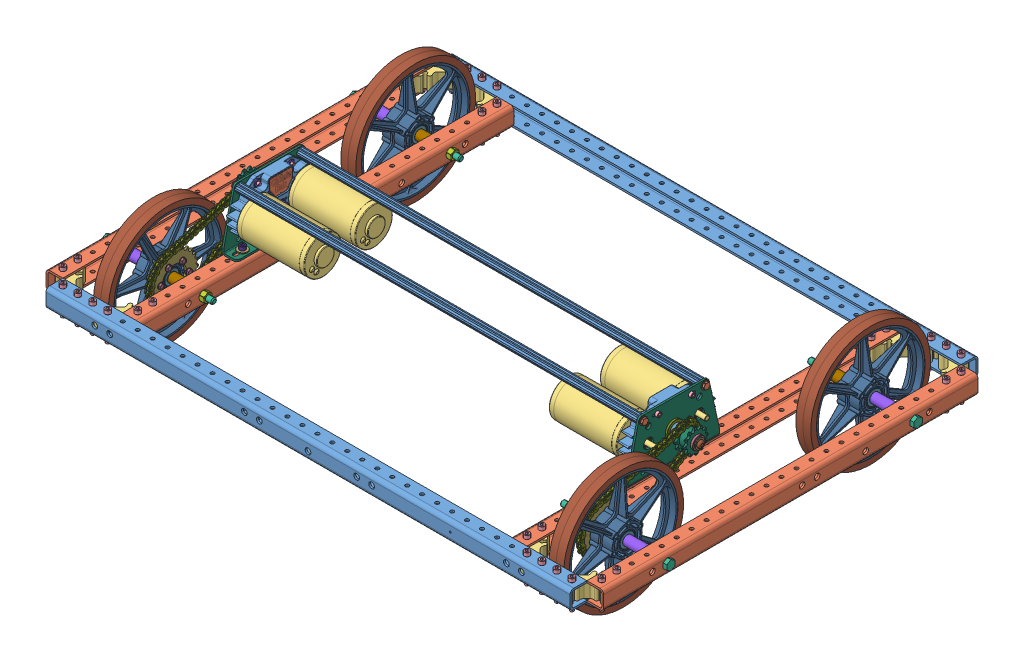
SolidWorks assembly 2011C-BaseWheelsCIMpleBoxWIDE, configuration Default. Lengths in mm.
Overall size (966.2 283.99 712.2).
231 component instances, 38 part files, 61 mates.
Components (placement in the parent):
- C-Base-Triangle-Mounts-no-bracket-WIDE-1: C-Base-Triangle-Mounts-no-bracket-WIDE [Default] at origin size (966.2 50.8 712.2)
  - C channel Outer-1: C channel Outer [Default] at (0 0 -317.4979) x (0 -1 0) z (0 0 1) size (31.75 889 28.57)
  - Short C channel-1: Short C channel [for WIDE frame] at (444.5 0 -25.4) x (0 1 0) z (-1 0 0) size (31.75 635 28.57)
  - Corner_Extrusion-2: Corner_Extrusion [Default] at (437.7662 0 -310.765) x (-0.707157 0 -0.707057) z (0 -1 0) size (90.51 36.63 25.4)
  - SHCS_1-6: SHCS_1 [1.75] at (457.2 -3.175 -279.4) x (0 -1 0) z (0 0 -1) size (50.8 9.4 9.4)
  - SHCS_1-7: SHCS_1 [1.75] at (457.2 -3.175 -304.8) x (0 -1 0) z (0 0 -1) size (50.8 9.4 9.4)
  - SHCS_1-8: SHCS_1 [1.75] at (431.8 -3.175 -330.1979) x (0 -1 0) z (0 0 -1) size (50.8 9.4 9.4)
  - SHCS_1-9: SHCS_1 [1.75] at (406.4 -3.175 -330.1979) x (0 -1 0) z (0 0 -1) size (50.8 9.4 9.4)
  - Quarer20_Nut-5: Quarer20_Nut [Default] at (457.2 -18.8595 -279.4) x (0.837169 0 -0.546944) z (0.546944 0 0.837169) size (14.11 5.97 11.11)
  - Quarer20_Nut-6: Quarer20_Nut [Default] at (457.2 -18.8595 -304.8) x (0.837169 0 -0.546944) z (0.546944 0 0.837169) size (14.11 5.97 11.11)
  - Quarer20_Nut-9: Quarer20_Nut [Default] at (406.4 -18.8595 -330.1979) x (0.837169 0 -0.546944) z (0.546944 0 0.837169) size (14.11 5.97 11.11)
  - Quarer20_Nut-12: Quarer20_Nut [Default] at (431.8 -18.8595 -330.1979) x (0.837169 0 -0.546944) z (0.546944 0 0.837169) size (14.11 5.97 11.11)
  - C channel Outer-4: C channel Outer [Default] at (0 0 317.4979) x (0 -1 0) z (0 0 -1) size (31.75 889 28.57)
  - Short C channel-3: Short C channel [for WIDE frame] at (-444.5 0 25.4) x (0 1 0) z (1 0 0) size (31.75 635 28.57)
  - SHCS_1-18: SHCS_1 [1.75] at (330.2 -3.175 -279.4) x (0 -1 0) z (0 0 1) size (50.8 9.4 9.4)
  - SHCS_1-19: SHCS_1 [1.75] at (330.2 -3.175 -304.8) x (0 -1 0) z (0 0 1) size (50.8 9.4 9.4)
  - SHCS_1-20: SHCS_1 [1.75] at (355.6 -3.175 -330.1979) x (0 -1 0) z (0 0 1) size (50.8 9.4 9.4)
  - SHCS_1-21: SHCS_1 [1.75] at (381 -3.175 -330.1979) x (0 -1 0) z (0 0 1) size (50.8 9.4 9.4)
  - Quarer20_Nut-21: Quarer20_Nut [Default] at (330.2 -18.8595 -279.4) x (-0.837169 0 -0.546944) z (0.546944 0 -0.837169) size (14.11 5.97 11.11)
  - Quarer20_Nut-22: Quarer20_Nut [Default] at (330.2 -18.8595 -304.8) x (-0.837169 0 -0.546944) z (0.546944 0 -0.837169) size (14.11 5.97 11.11)
  - Quarer20_Nut-23: Quarer20_Nut [Default] at (381 -18.8595 -330.1979) x (-0.837169 0 -0.546944) z (0.546944 0 -0.837169) size (14.11 5.97 11.11)
  - Quarer20_Nut-24: Quarer20_Nut [Default] at (355.6 -18.8595 -330.1979) x (-0.837169 0 -0.546944) z (0.546944 0 -0.837169) size (14.11 5.97 11.11)
  - Corner_Extrusion-5: Corner_Extrusion [Default] at (349.6338 0 -310.765) x (0.707157 0 -0.707057) z (0 1 0) size (90.51 36.63 25.4)
  - SHCS_1-30: SHCS_1 [1.75] at (330.2 -3.175 279.4) x (0 -1 0) z (0 0 1) size (50.8 9.4 9.4)
  - SHCS_1-31: SHCS_1 [1.75] at (330.2 -3.175 304.8) x (0 -1 0) z (0 0 1) size (50.8 9.4 9.4)
  - SHCS_1-32: SHCS_1 [1.75] at (355.6 -3.175 330.1979) x (0 -1 0) z (0 0 1) size (50.8 9.4 9.4)
  - SHCS_1-33: SHCS_1 [1.75] at (381 -3.175 330.1979) x (0 -1 0) z (0 0 1) size (50.8 9.4 9.4)
  - Quarer20_Nut-33: Quarer20_Nut [Default] at (330.2 -18.8595 279.4) x (-0.837169 0 0.546944) z (-0.546944 0 -0.837169) size (14.11 5.97 11.11)
  - Quarer20_Nut-34: Quarer20_Nut [Default] at (330.2 -18.8595 304.8) x (-0.837169 0 0.546944) z (-0.546944 0 -0.837169) size (14.11 5.97 11.11)
  - Quarer20_Nut-35: Quarer20_Nut [Default] at (381 -18.8595 330.1979) x (-0.837169 0 0.546944) z (-0.546944 0 -0.837169) size (14.11 5.97 11.11)
  - Quarer20_Nut-36: Quarer20_Nut [Default] at (355.6 -18.8595 330.1979) x (-0.837169 0 0.546944) z (-0.546944 0 -0.837169) size (14.11 5.97 11.11)
  - Corner_Extrusion-8: Corner_Extrusion [Default] at (349.6338 0 310.765) x (0.707157 0 0.707057) z (0 -1 0) size (90.51 36.63 25.4)
  - SHCS_1-34: SHCS_1 [1.75] at (457.2 -3.175 279.4) x (0 -1 0) z (0 0 -1) size (50.8 9.4 9.4)
  - SHCS_1-35: SHCS_1 [1.75] at (457.2 -3.175 304.8) x (0 -1 0) z (0 0 -1) size (50.8 9.4 9.4)
  - SHCS_1-36: SHCS_1 [1.75] at (431.8 -3.175 330.1979) x (0 -1 0) z (0 0 -1) size (50.8 9.4 9.4)
  - SHCS_1-37: SHCS_1 [1.75] at (406.4 -3.175 330.1979) x (0 -1 0) z (0 0 -1) size (50.8 9.4 9.4)
  - Corner_Extrusion-9: Corner_Extrusion [Default] at (437.7662 0 310.765) x (-0.707157 0 0.707057) z (0 1 0) size (90.51 36.63 25.4)
  - Quarer20_Nut-37: Quarer20_Nut [Default] at (457.2 -18.8595 279.4) x (0.837169 0 0.546944) z (-0.546944 0 0.837169) size (14.11 5.97 11.11)
  - Quarer20_Nut-38: Quarer20_Nut [Default] at (457.2 -18.8595 304.8) x (0.837169 0 0.546944) z (-0.546944 0 0.837169) size (14.11 5.97 11.11)
  - Quarer20_Nut-39: Quarer20_Nut [Default] at (431.8 -18.8595 330.1979) x (0.837169 0 0.546944) z (-0.546944 0 0.837169) size (14.11 5.97 11.11)
  - Quarer20_Nut-40: Quarer20_Nut [Default] at (406.4 -18.8595 330.1979) x (0.837169 0 0.546944) z (-0.546944 0 0.837169) size (14.11 5.97 11.11)
  - SHCS_1-38: SHCS_1 [1.75] at (-330.2 -3.175 -279.4) x (0 -1 0) z (0 0 -1) size (50.8 9.4 9.4)
  - SHCS_1-39: SHCS_1 [1.75] at (-330.2 -3.175 -304.8) x (0 -1 0) z (0 0 -1) size (50.8 9.4 9.4)
  - SHCS_1-40: SHCS_1 [1.75] at (-355.6 -3.175 -330.1979) x (0 -1 0) z (0 0 -1) size (50.8 9.4 9.4)
  - SHCS_1-41: SHCS_1 [1.75] at (-381 -3.175 -330.1979) x (0 -1 0) z (0 0 -1) size (50.8 9.4 9.4)
  - Quarer20_Nut-41: Quarer20_Nut [Default] at (-330.2 -18.8595 -279.4) x (0.837169 0 -0.546944) z (0.546944 0 0.837169) size (14.11 5.97 11.11)
  - Quarer20_Nut-42: Quarer20_Nut [Default] at (-330.2 -18.8595 -304.8) x (0.837169 0 -0.546944) z (0.546944 0 0.837169) size (14.11 5.97 11.11)
  - Quarer20_Nut-43: Quarer20_Nut [Default] at (-381 -18.8595 -330.1979) x (0.837169 0 -0.546944) z (0.546944 0 0.837169) size (14.11 5.97 11.11)
  - Quarer20_Nut-44: Quarer20_Nut [Default] at (-355.6 -18.8595 -330.1979) x (0.837169 0 -0.546944) z (0.546944 0 0.837169) size (14.11 5.97 11.11)
  - Corner_Extrusion-10: Corner_Extrusion [Default] at (-349.6338 0 -310.765) x (-0.707157 0 -0.707057) z (0 -1 0) size (90.51 36.63 25.4)
  - SHCS_1-42: SHCS_1 [1.75] at (-330.2 -3.175 279.4) x (0 -1 0) z (0 0 -1) size (50.8 9.4 9.4)
  - SHCS_1-43: SHCS_1 [1.75] at (-330.2 -3.175 304.8) x (0 -1 0) z (0 0 -1) size (50.8 9.4 9.4)
  - SHCS_1-44: SHCS_1 [1.75] at (-355.6 -3.175 330.1979) x (0 -1 0) z (0 0 -1) size (50.8 9.4 9.4)
  - SHCS_1-45: SHCS_1 [1.75] at (-381 -3.175 330.1979) x (0 -1 0) z (0 0 -1) size (50.8 9.4 9.4)
  - Quarer20_Nut-45: Quarer20_Nut [Default] at (-330.2 -18.8595 279.4) x (0.837169 0 0.546944) z (-0.546944 0 0.837169) size (14.11 5.97 11.11)
  - Quarer20_Nut-46: Quarer20_Nut [Default] at (-330.2 -18.8595 304.8) x (0.837169 0 0.546944) z (-0.546944 0 0.837169) size (14.11 5.97 11.11)
  - Quarer20_Nut-47: Quarer20_Nut [Default] at (-381 -18.8595 330.1979) x (0.837169 0 0.546944) z (-0.546944 0 0.837169) size (14.11 5.97 11.11)
  - Quarer20_Nut-48: Quarer20_Nut [Default] at (-355.6 -18.8595 330.1979) x (0.837169 0 0.546944) z (-0.546944 0 0.837169) size (14.11 5.97 11.11)
  - Corner_Extrusion-11: Corner_Extrusion [Default] at (-349.6338 0 310.765) x (-0.707157 0 0.707057) z (0 1 0) size (90.51 36.63 25.4)
  - SHCS_1-46: SHCS_1 [1.75] at (-457.2 -3.175 279.4) x (0 -1 0) z (0 0 1) size (50.8 9.4 9.4)
  - SHCS_1-47: SHCS_1 [1.75] at (-457.2 -3.175 304.8) x (0 -1 0) z (0 0 1) size (50.8 9.4 9.4)
  - SHCS_1-48: SHCS_1 [1.75] at (-431.8 -3.175 330.1979) x (0 -1 0) z (0 0 1) size (50.8 9.4 9.4)
  - SHCS_1-49: SHCS_1 [1.75] at (-406.4 -3.175 330.1979) x (0 -1 0) z (0 0 1) size (50.8 9.4 9.4)
  - Corner_Extrusion-12: Corner_Extrusion [Default] at (-437.7662 0 310.765) x (0.707157 0 0.707057) z (0 -1 0) size (90.51 36.63 25.4)
  - Quarer20_Nut-49: Quarer20_Nut [Default] at (-457.2 -18.8595 279.4) x (-0.837169 0 0.546944) z (-0.546944 0 -0.837169) size (14.11 5.97 11.11)
  - Quarer20_Nut-50: Quarer20_Nut [Default] at (-457.2 -18.8595 304.8) x (-0.837169 0 0.546944) z (-0.546944 0 -0.837169) size (14.11 5.97 11.11)
  - Quarer20_Nut-51: Quarer20_Nut [Default] at (-431.8 -18.8595 330.1979) x (-0.837169 0 0.546944) z (-0.546944 0 -0.837169) size (14.11 5.97 11.11)
  - Quarer20_Nut-52: Quarer20_Nut [Default] at (-406.4 -18.8595 330.1979) x (-0.837169 0 0.546944) z (-0.546944 0 -0.837169) size (14.11 5.97 11.11)
  - SHCS_1-50: SHCS_1 [1.75] at (-457.2 -3.175 -304.8) x (0 -1 0) z (0 0 1) size (50.8 9.4 9.4)
  - Corner_Extrusion-13: Corner_Extrusion [Default] at (-437.7662 0 -310.765) x (0.707157 0 -0.707057) z (0 1 0) size (90.51 36.63 25.4)
  - SHCS_1-51: SHCS_1 [1.75] at (-431.8 -3.175 -330.1979) x (0 -1 0) z (0 0 1) size (50.8 9.4 9.4)
  - SHCS_1-52: SHCS_1 [1.75] at (-406.4 -3.175 -330.1979) x (0 -1 0) z (0 0 1) size (50.8 9.4 9.4)
  - SHCS_1-53: SHCS_1 [1.75] at (-457.2 -3.175 -279.4) x (0 -1 0) z (0 0 1) size (50.8 9.4 9.4)
  - Quarer20_Nut-53: Quarer20_Nut [Default] at (-457.2 -18.8595 -279.4) x (-0.837169 0 -0.546944) z (0.546944 0 -0.837169) size (14.11 5.97 11.11)
  - Quarer20_Nut-54: Quarer20_Nut [Default] at (-457.2 -18.8595 -304.8) x (-0.837169 0 -0.546944) z (0.546944 0 -0.837169) size (14.11 5.97 11.11)
  - Quarer20_Nut-55: Quarer20_Nut [Default] at (-431.8 -18.8595 -330.1979) x (-0.837169 0 -0.546944) z (0.546944 0 -0.837169) size (14.11 5.97 11.11)
  - Quarer20_Nut-56: Quarer20_Nut [Default] at (-406.4 -18.8595 -330.1979) x (-0.837169 0 -0.546944) z (0.546944 0 -0.837169) size (14.11 5.97 11.11)
  - Short C channel-8: Short C channel [for WIDE frame] at (342.9 0 25.4) x (0 1 0) z (1 0 0) size (31.75 635 28.57)
  - Short C channel-10: Short C channel [for WIDE frame] at (-342.9 0 -25.4) x (0 1 0) z (-1 0 0) size (31.75 635 28.57)
- 375x7_hex bolt-1: 375x7_hex bolt [Default] at (479.298 1.905 209.55) x (0 -1 0) z (0 0 1) size (16.53 184.02 14.31)
- 3-8-16 Nut_-1: 3-8-16 Nut_ [Default] at (305.943 1.905 209.55) x (0 -1 0) z (0 0 1) size (17.45 8.38 14.1)
- 2550x375_Spacer-1: 2550x375_Spacer [Default] at (438.15 1.905 209.55) x (0 0 1) z (-1 0 0) size (17.12 17.12 64.77)
- 1940x375_Spacer-1: 1940x375_Spacer [Default] at (341.376 1.905 209.55) x (0 0 1) z (-1 0 0) size (16.84 16.84 49.28)
- Wheel and hardware-1: Wheel and hardware [with sprocket] at (386.332 1.905 209.55) x (0 -0.118491 -0.992955) z (1 0 0) size (204.98 204.98 45.74)
  - 2010 8 hub-1: 2010 8 hub [Default] at origin size (190.41 190.41 38.18)
  - 2010 8 tread-1: 2010 8 tread [Default] at (0 0 -0.0025) x (1 0 0) z (0 1 0) size (204.98 25.4 204.98)
  - S35-26LE_-1: S35-26LE_ [Default] at (0 0 -21.082) x (0.866025 0.5 0) z (0 0 1) size (83.7 84.16 4.06)
  - 10-24x750_thread forming screw-1: 10-24x750_thread forming screw [Default] at (20.6222 11.9062 -26.6446) x (0 0 1) z (0 -1 0) size (17.83 9.75 9.75)
  - 10-24x750_thread forming screw-2: 10-24x750_thread forming screw [Default] at (20.6222 -11.9062 -26.6446) x (0 0 1) z (-0.866025 -0.5 0) size (17.83 9.75 9.75)
  - 10-24x750_thread forming screw-3: 10-24x750_thread forming screw [Default] at (0 -23.8125 -26.6446) x (0 0 1) z (-0.866025 0.5 0) size (17.83 9.75 9.75)
  - 10-24x750_thread forming screw-4: 10-24x750_thread forming screw [Default] at (-20.6222 -11.9062 -26.6446) x (0 0 1) z (0 1 0) size (17.83 9.75 9.75)
  - 10-24x750_thread forming screw-5: 10-24x750_thread forming screw [Default] at (-20.6222 11.9062 -26.6446) x (0 0 1) z (0.866025 0.5 0) size (17.83 9.75 9.75)
  - 10-24x750_thread forming screw-6: 10-24x750_thread forming screw [Default] at (0 23.8125 -26.6446) x (0 0 1) z (0.866025 -0.5 0) size (17.83 9.75 9.75)
  - 1614Z Bearning-1: 1614Z Bearning [Default] at (0 0 -14.099) size (28.57 28.57 9.4)
  - 1614Z Bearning-3: 1614Z Bearning [Default] at (0 0 14.099) x (-1 0 0) z (0 0 -1) size (28.57 28.57 9.4)
- CIMple_Box-1: CIMple_Box [Default-_flexible1] at (341.3122 65.4047 69.85) x (0 0 1) z (-1 0 0) size (155.57 95.25 190.12) (flexible)
  - Single_d02_-1: Single_d02_ [Default] at (0 0 -3.175) x (1 0 0) z (0 0 -1) size (155.57 95.25 25.4)
  - fr-8-zz-1: fr-8-zz [Default] at (0 0 -6.3627) x (1 0 0) z (0 0 -1) size (31.74 31.74 7.94)
  - Single_d03_2_-1: Single_d03_2_ [Default] at (0 0 14.7574) x (0 0 1) z (-0.675773 0.73711 0) size (77.22 12.7 14.66)
  - 56 Tooth Output Gear-1: 56 Tooth Output Gear [Default] at (0 0 6.5151) x (0.675773 -0.73711 0) z (0 0 1) size (71.75 71.75 9.88)
  - Single d01_1-1: Single d01_1 [Default] x (-1 0 0) z (0 0 1) size (147.73 90.64 24.77)
  - CIMple Box Sticker 1-1: CIMple Box Sticker 1 [Default] at (-0.0933 12.1703 19.304) size (39.12 30.48 0.53)
  - CIM_motor_2-1: CIM_motor_2 [Default] at (-43.2562 0 138.4173) x (0 1 0) z (-1 0 0) size (64.01 154.93 64.01)
  - 10-32x0625_shcs 1-1: 10-32x0625_shcs 1 [Default] at (-43.2499 25.39 29.2608) x (1 0 0) z (0 1 0) size (7.82 20.65 7.82)
  - 10-32x0625_shcs 1-2: 10-32x0625_shcs 1 [Default] at (-43.2562 -25.4 29.2608) x (1 0 0) z (0 1 0) size (7.82 20.65 7.82)
  - 2mmx2mmx10mm_key-1: 2mmx2mmx10mm_key [Default] at (-43.2562 -3.7999 3.7259) x (1 0 0) z (0 -1 0) size (2 10 2)
  - r6zz 1-1: r6zz 1 [Default] at (0 0 11.8618) size (22.23 22.23 7.11)
  - 10-32x0625_shcs 1-3: 10-32x0625_shcs 1 [Default] at (43.2499 25.39 29.2608) x (-1 0 0) z (0 -1 0) size (7.82 20.65 7.82)
  - CIM_motor_2-2: CIM_motor_2 [Default] at (43.2682 0 138.4173) x (0 1 0) z (-1 0 0) size (64.01 154.93 64.01)
  - 10-32x0625_shcs 1-4: 10-32x0625_shcs 1 [Default] at (43.2562 -25.4 29.2608) x (-1 0 0) z (0 -1 0) size (7.82 20.65 7.82)
  - 2mmx2mmx10mm_key-5: 2mmx2mmx10mm_key [Default] at (43.2682 -3.7999 3.7259) x (1 0 0) z (0 -1 0) size (2 10 2)
  - 12x520 CIM Gear-1: 12x520 CIM Gear [Default] at (43.2682 0 8.382) x (0.080306 -0.99677 0) z (0 0 1) size (19.3 19.3 13.21)
  - 12x520 CIM Gear-2: 12x520 CIM Gear [Default] at (-43.2562 0 8.382) x (0.086089 -0.996287 0) z (0 0 1) size (19.3 19.3 13.21)
  - 10-32 nylock_nut_2-1: 10-32 nylock_nut_2 [Default] at (-28.575 36.5125 4.525) x (0.5 0.866025 0) z (0.866025 -0.5 0) size (9.53 5.95 12.1)
  - 10-32x0625_shcs 1-5: 10-32x0625_shcs 1 [Default] at (-28.575 36.5125 12.7) x (1 0 0) z (0 1 0) size (7.82 20.65 7.82)
  - 10-32x0625_shcs 1-6: 10-32x0625_shcs 1 [Default] at (28.575 36.5125 12.7) x (1 0 0) z (0 1 0) size (7.82 20.65 7.82)
  - 10-32x0625_shcs 1-7: 10-32x0625_shcs 1 [Default] at (-28.575 -36.5125 12.7) x (1 0 0) z (0 1 0) size (7.82 20.65 7.82)
  - 10-32x0625_shcs 1-8: 10-32x0625_shcs 1 [Default] at (28.575 -36.5125 12.7) x (1 0 0) z (0 1 0) size (7.82 20.65 7.82)
  - 10-32 nylock_nut_2-2: 10-32 nylock_nut_2 [Default] at (28.575 36.5125 4.525) x (0.5 0.866025 0) z (0.866025 -0.5 0) size (9.53 5.95 12.1)
  - 10-32 nylock_nut_2-3: 10-32 nylock_nut_2 [Default] at (-28.575 -36.5125 4.525) x (0.5 0.866025 0) z (0.866025 -0.5 0) size (9.53 5.95 12.1)
  - 10-32 nylock_nut_2-4: 10-32 nylock_nut_2 [Default] at (28.575 -36.5125 4.525) x (0.5 0.866025 0) z (0.866025 -0.5 0) size (9.53 5.95 12.1)
  - 8mm_spring_clip-1: 8mm_spring_clip [Default] at (43.2682 0 0.8264) x (-0.080306 0.99677 0) z (0.99677 0.080306 0) size (14.73 1.16 14.73)
  - 8mm_spring_clip-2: 8mm_spring_clip [Default] at (-43.2562 0 0.8264) x (-0.086089 0.996287 0) z (0.996287 0.086089 0) size (14.73 1.16 14.73)
  - 125x124x700_key-1: 125x124x700_key [Default] at (4.6775 4.2194 -21.6662) x (0.73711 0.675773 0) z (-0.675773 0.73711 0) size (3.17 17.78 3.15)
  - 14-20x0500_bhcs-1: 14-20x0500_bhcs [Default] at (0 0 -34.925) x (0.675773 -0.73711 0) z (0.73711 0.675773 0) size (11.68 16.77 11.68)
  - 250_washer 1-1: 250_washer 1 [Default] at (0 0 -47.625) x (0.675773 -0.73711 0) z (0.73711 0.675773 0) size (16.26 1.57 16.26)
  - 177x500_spacer_3-1: 177x500_spacer_3 [Default] at (0 0 -46.0502) x (0.675773 -0.73711 0) z (0.73711 0.675773 0) size (21.34 4.5 21.34)
  - 595x500_spacer 3-1: 595x500_spacer 3 [Default] at (0 0 -21.4757) x (-0.73711 -0.675773 0) z (0.675773 -0.73711 0) size (21.34 15.11 21.34)
  - S35-12DHE Sprocket-1: S35-12DHE Sprocket [Default] at (0 0 -31.7754) x (-0.73711 -0.675773 0) z (0 0 1) size (40.24 40.24 19.56)
- Chain 2-1: Chain 2 [Default] at (365.2898 65.4047 69.85) x (0 0 1) z (-1 0 0) size (208.45 129.75 10.28)
- 250_washer 1-3: 250_washer 1 [Default] at (330.2 20.6248 127) size (16.26 1.57 16.26)
- 250_washer 1-4: 250_washer 1 [Default] at (330.2 20.6248 0) size (16.26 1.57 16.26)
- 1-4-20x0625 SHCS 4-4: 1-4-20x0625 SHCS 4 [Default] at (330.2 20.6248 0) x (1 0 0) z (0 1 0) size (9.4 9.4 25.4)
- 1-4-20x0625 SHCS 4-5: 1-4-20x0625 SHCS 4 [Default] at (330.2 20.6248 127) x (1 0 0) z (0 1 0) size (9.4 9.4 25.4)
- 14-20_nylock_nut 4-1: 14-20_nylock_nut 4 [Default] at (330.2 5.0292 127) x (0.837169 0 0.546944) z (0.546944 0 -0.837169) size (12.7 7.67 11.1)
- 14-20_nylock_nut 4-2: 14-20_nylock_nut 4 [Default] at (330.2 5.0292 0) x (0.837169 0 0.546944) z (0.546944 0 -0.837169) size (12.7 7.67 11.1)
- 3-8-16 Nut_-2: 3-8-16 Nut_ [Default] at (305.943 1.905 -209.55) x (0 -1 0) z (0 0 1) size (17.45 8.38 14.1)
- 1940x375_Spacer-2: 1940x375_Spacer [Default] at (341.376 1.905 -209.55) x (0 0 1) z (-1 0 0) size (16.84 16.84 49.28)
- 375x7_hex bolt-2: 375x7_hex bolt [Default] at (479.298 1.905 -209.55) x (0 -1 0) z (0 0 1) size (16.53 184.02 14.31)
- 2550x375_Spacer-2: 2550x375_Spacer [Default] at (438.15 1.905 -209.55) x (0 0 1) z (-1 0 0) size (17.12 17.12 64.77)
- 3-8-16 Nut_-3: 3-8-16 Nut_ [Default] at (-305.943 1.905 -209.55) x (0 -1 0) z (0 0 -1) size (17.45 8.38 14.1)
- 1940x375_Spacer-3: 1940x375_Spacer [Default] at (-341.376 1.905 -209.55) x (0 0 -1) z (1 0 0) size (16.84 16.84 49.28)
- 375x7_hex bolt-3: 375x7_hex bolt [Default] at (-479.298 1.905 -209.55) x (0 -1 0) z (0 0 -1) size (16.53 184.02 14.31)
- 2550x375_Spacer-3: 2550x375_Spacer [Default] at (-438.15 1.905 -209.55) x (0 0 -1) z (1 0 0) size (17.12 17.12 64.77)
- 375x7_hex bolt-4: 375x7_hex bolt [Default] at (-479.298 1.905 209.55) x (0 -1 0) z (0 0 -1) size (16.53 184.02 14.31)
- 3-8-16 Nut_-4: 3-8-16 Nut_ [Default] at (-305.943 1.905 209.55) x (0 -1 0) z (0 0 -1) size (17.45 8.38 14.1)
- 2550x375_Spacer-4: 2550x375_Spacer [Default] at (-438.15 1.905 209.55) x (0 0 -1) z (1 0 0) size (17.12 17.12 64.77)
- 1940x375_Spacer-4: 1940x375_Spacer [Default] at (-341.376 1.905 209.55) x (0 0 -1) z (1 0 0) size (16.84 16.84 49.28)
- CIMple_Box-2: CIMple_Box [Default-_flexible2] at (-341.3122 65.4047 69.85) x (0 0 -1) z (1 0 0) size (155.57 95.25 190.12) (flexible)
  - Single_d02_-1: Single_d02_ [Default] at (0 0 -3.175) x (1 0 0) z (0 0 -1) size (155.57 95.25 25.4)
  - fr-8-zz-1: fr-8-zz [Default] at (0 0 -6.3627) x (1 0 0) z (0 0 -1) size (31.74 31.74 7.94)
  - Single_d03_2_-1: Single_d03_2_ [Default] at (0 0 14.7574) x (0 0 1) z (-0.901979 -0.431779 0) size (77.22 12.7 14.66)
  - 56 Tooth Output Gear-1: 56 Tooth Output Gear [Default] at (0 0 6.5151) x (0.901979 0.431779 0) z (0 0 1) size (71.75 71.75 9.88)
  - Single d01_1-1: Single d01_1 [Default] x (-1 0 0) z (0 0 1) size (147.73 90.64 24.77)
  - CIMple Box Sticker 1-1: CIMple Box Sticker 1 [Default] at (-0.0933 12.1703 19.304) size (39.12 30.48 0.53)
  - CIM_motor_2-1: CIM_motor_2 [Default] at (-43.2562 0 138.4173) x (0 1 0) z (-1 0 0) size (64.01 154.93 64.01)
  - 10-32x0625_shcs 1-1: 10-32x0625_shcs 1 [Default] at (-43.2499 25.39 29.2608) x (1 0 0) z (0 1 0) size (7.82 20.65 7.82)
  - 10-32x0625_shcs 1-2: 10-32x0625_shcs 1 [Default] at (-43.2562 -25.4 29.2608) x (1 0 0) z (0 1 0) size (7.82 20.65 7.82)
  - 2mmx2mmx10mm_key-1: 2mmx2mmx10mm_key [Default] at (-43.2562 -3.7999 3.7259) x (1 0 0) z (0 -1 0) size (2 10 2)
  - r6zz 1-1: r6zz 1 [Default] at (0 0 11.8618) size (22.23 22.23 7.11)
  - 10-32x0625_shcs 1-3: 10-32x0625_shcs 1 [Default] at (43.2499 25.39 29.2608) x (-1 0 0) z (0 -1 0) size (7.82 20.65 7.82)
  - CIM_motor_2-2: CIM_motor_2 [Default] at (43.2682 0 138.4173) x (0 1 0) z (-1 0 0) size (64.01 154.93 64.01)
  - 10-32x0625_shcs 1-4: 10-32x0625_shcs 1 [Default] at (43.2562 -25.4 29.2608) x (-1 0 0) z (0 -1 0) size (7.82 20.65 7.82)
  - 2mmx2mmx10mm_key-5: 2mmx2mmx10mm_key [Default] at (43.2682 -3.7999 3.7259) x (1 0 0) z (0 -1 0) size (2 10 2)
  - 12x520 CIM Gear-1: 12x520 CIM Gear [Default] at (43.2682 0 8.382) x (0.908929 0.416952 0) z (0 0 1) size (19.3 19.3 13.21)
  - 12x520 CIM Gear-2: 12x520 CIM Gear [Default] at (-43.2562 0 8.382) x (0.906494 0.422219 0) z (0 0 1) size (19.3 19.3 13.21)
  - 10-32 nylock_nut_2-1: 10-32 nylock_nut_2 [Default] at (-28.575 36.5125 4.525) x (0.5 0.866025 0) z (0.866025 -0.5 0) size (9.53 5.95 12.1)
  - 10-32x0625_shcs 1-5: 10-32x0625_shcs 1 [Default] at (-28.575 36.5125 12.7) x (1 0 0) z (0 1 0) size (7.82 20.65 7.82)
  - 10-32x0625_shcs 1-6: 10-32x0625_shcs 1 [Default] at (28.575 36.5125 12.7) x (1 0 0) z (0 1 0) size (7.82 20.65 7.82)
  - 10-32x0625_shcs 1-7: 10-32x0625_shcs 1 [Default] at (-28.575 -36.5125 12.7) x (1 0 0) z (0 1 0) size (7.82 20.65 7.82)
  - 10-32x0625_shcs 1-8: 10-32x0625_shcs 1 [Default] at (28.575 -36.5125 12.7) x (1 0 0) z (0 1 0) size (7.82 20.65 7.82)
  - 10-32 nylock_nut_2-2: 10-32 nylock_nut_2 [Default] at (28.575 36.5125 4.525) x (0.5 0.866025 0) z (0.866025 -0.5 0) size (9.53 5.95 12.1)
  - 10-32 nylock_nut_2-3: 10-32 nylock_nut_2 [Default] at (-28.575 -36.5125 4.525) x (0.5 0.866025 0) z (0.866025 -0.5 0) size (9.53 5.95 12.1)
  - 10-32 nylock_nut_2-4: 10-32 nylock_nut_2 [Default] at (28.575 -36.5125 4.525) x (0.5 0.866025 0) z (0.866025 -0.5 0) size (9.53 5.95 12.1)
  - 8mm_spring_clip-1: 8mm_spring_clip [Default] at (43.2682 0 0.8264) x (-0.908929 -0.416952 0) z (-0.416952 0.908929 0) size (14.73 1.16 14.73)
  - 8mm_spring_clip-2: 8mm_spring_clip [Default] at (-43.2562 0 0.8264) x (-0.906494 -0.422219 0) z (-0.422219 0.906494 0) size (14.73 1.16 14.73)
  - 125x124x700_key-1: 125x124x700_key [Default] at (-2.674 5.7037 -21.6662) x (-0.431779 0.901979 0) z (-0.901979 -0.431779 0) size (3.17 17.78 3.15)
  - 14-20x0500_bhcs-1: 14-20x0500_bhcs [Default] at (0 0 -34.925) x (0.901979 0.431779 0) z (-0.431779 0.901979 0) size (11.68 16.77 11.68)
  - 250_washer 1-1: 250_washer 1 [Default] at (0 0 -47.625) x (0.901979 0.431779 0) z (-0.431779 0.901979 0) size (16.26 1.57 16.26)
  - 177x500_spacer_3-1: 177x500_spacer_3 [Default] at (0 0 -46.0502) x (0.901979 0.431779 0) z (-0.431779 0.901979 0) size (21.34 4.5 21.34)
  - 595x500_spacer 3-1: 595x500_spacer 3 [Default] at (0 0 -21.4757) x (0.431779 -0.901979 0) z (0.901979 0.431779 0) size (21.34 15.11 21.34)
  - S35-12DHE Sprocket-1: S35-12DHE Sprocket [Default] at (0 0 -31.7754) x (0.431779 -0.901979 0) z (0 0 1) size (40.24 40.24 19.56)
- Wheel and hardware-2: Wheel and hardware [with sprocket] at (-386.332 1.905 209.55) x (0 0.550976 0.834521) z (-1 0 0) size (204.98 204.98 45.74)
  - 2010 8 hub-1: 2010 8 hub [Default] at origin size (190.41 190.41 38.18)
  - 2010 8 tread-1: 2010 8 tread [Default] at (0 0 -0.0025) x (1 0 0) z (0 1 0) size (204.98 25.4 204.98)
  - S35-26LE_-1: S35-26LE_ [Default] at (0 0 -21.082) x (0.866025 0.5 0) z (0 0 1) size (83.7 84.16 4.06)
  - 10-24x750_thread forming screw-1: 10-24x750_thread forming screw [Default] at (20.6222 11.9062 -26.6446) x (0 0 1) z (0 -1 0) size (17.83 9.75 9.75)
  - 10-24x750_thread forming screw-2: 10-24x750_thread forming screw [Default] at (20.6222 -11.9062 -26.6446) x (0 0 1) z (-0.866025 -0.5 0) size (17.83 9.75 9.75)
  - 10-24x750_thread forming screw-3: 10-24x750_thread forming screw [Default] at (0 -23.8125 -26.6446) x (0 0 1) z (-0.866025 0.5 0) size (17.83 9.75 9.75)
  - 10-24x750_thread forming screw-4: 10-24x750_thread forming screw [Default] at (-20.6222 -11.9062 -26.6446) x (0 0 1) z (0 1 0) size (17.83 9.75 9.75)
  - 10-24x750_thread forming screw-5: 10-24x750_thread forming screw [Default] at (-20.6222 11.9062 -26.6446) x (0 0 1) z (0.866025 0.5 0) size (17.83 9.75 9.75)
  - 10-24x750_thread forming screw-6: 10-24x750_thread forming screw [Default] at (0 23.8125 -26.6446) x (0 0 1) z (0.866025 -0.5 0) size (17.83 9.75 9.75)
  - 1614Z Bearning-1: 1614Z Bearning [Default] at (0 0 -14.099) size (28.57 28.57 9.4)
  - 1614Z Bearning-3: 1614Z Bearning [Default] at (0 0 14.099) x (-1 0 0) z (0 0 -1) size (28.57 28.57 9.4)
- Chain 2-2: Chain 2 [Default] at (-365.2898 65.4047 69.85) x (0 0 1) z (-1 0 0) size (208.45 129.75 10.28)
- Wheel and hardware-3: Wheel and hardware [without sprocket] at (-385.574 1.905 -209.55) x (0 0 -1) z (1 0 0) size (204.98 204.98 38.18)
  - 2010 8 hub-1: 2010 8 hub [Default] at origin size (190.41 190.41 38.18)
  - 2010 8 tread-1: 2010 8 tread [Default] at (0 0 -0.0025) x (1 0 0) z (0 1 0) size (204.98 25.4 204.98)
  - S35-26LE_-1: S35-26LE_ [Default] at (0 0 -21.082) x (0.866025 0.5 0) z (0 0 1) size (83.7 84.16 4.06) (suppressed, hidden)
  - 10-24x750_thread forming screw-1: 10-24x750_thread forming screw [Default] at (20.6222 11.9062 -26.6446) x (0 0 1) z (0 -1 0) size (17.83 9.75 9.75) (suppressed, hidden)
  - 10-24x750_thread forming screw-2: 10-24x750_thread forming screw [Default] at (20.6222 -11.9062 -26.6446) x (0 0 1) z (-0.866025 -0.5 0) size (17.83 9.75 9.75) (suppressed, hidden)
  - 10-24x750_thread forming screw-3: 10-24x750_thread forming screw [Default] at (0 -23.8125 -26.6446) x (0 0 1) z (-0.866025 0.5 0) size (17.83 9.75 9.75) (suppressed, hidden)
  - 10-24x750_thread forming screw-4: 10-24x750_thread forming screw [Default] at (-20.6222 -11.9062 -26.6446) x (0 0 1) z (0 1 0) size (17.83 9.75 9.75) (suppressed, hidden)
  - 10-24x750_thread forming screw-5: 10-24x750_thread forming screw [Default] at (-20.6222 11.9062 -26.6446) x (0 0 1) z (0.866025 0.5 0) size (17.83 9.75 9.75) (suppressed, hidden)
  - 10-24x750_thread forming screw-6: 10-24x750_thread forming screw [Default] at (0 23.8125 -26.6446) x (0 0 1) z (0.866025 -0.5 0) size (17.83 9.75 9.75) (suppressed, hidden)
  - 1614Z Bearning-1: 1614Z Bearning [Default] at (0 0 -14.099) size (28.57 28.57 9.4)
  - 1614Z Bearning-3: 1614Z Bearning [Default] at (0 0 14.099) x (-1 0 0) z (0 0 -1) size (28.57 28.57 9.4)
- Wheel and hardware-4: Wheel and hardware [without sprocket] at (386.332 1.905 -209.55) x (0 0 -1) z (1 0 0) size (204.98 204.98 38.18)
  - 2010 8 hub-1: 2010 8 hub [Default] at origin size (190.41 190.41 38.18)
  - 2010 8 tread-1: 2010 8 tread [Default] at (0 0 -0.0025) x (1 0 0) z (0 1 0) size (204.98 25.4 204.98)
  - S35-26LE_-1: S35-26LE_ [Default] at (0 0 -21.082) x (0.866025 0.5 0) z (0 0 1) size (83.7 84.16 4.06) (suppressed, hidden)
  - 10-24x750_thread forming screw-1: 10-24x750_thread forming screw [Default] at (20.6222 11.9062 -26.6446) x (0 0 1) z (0 -1 0) size (17.83 9.75 9.75) (suppressed, hidden)
  - 10-24x750_thread forming screw-2: 10-24x750_thread forming screw [Default] at (20.6222 -11.9062 -26.6446) x (0 0 1) z (-0.866025 -0.5 0) size (17.83 9.75 9.75) (suppressed, hidden)
  - 10-24x750_thread forming screw-3: 10-24x750_thread forming screw [Default] at (0 -23.8125 -26.6446) x (0 0 1) z (-0.866025 0.5 0) size (17.83 9.75 9.75) (suppressed, hidden)
  - 10-24x750_thread forming screw-4: 10-24x750_thread forming screw [Default] at (-20.6222 -11.9062 -26.6446) x (0 0 1) z (0 1 0) size (17.83 9.75 9.75) (suppressed, hidden)
  - 10-24x750_thread forming screw-5: 10-24x750_thread forming screw [Default] at (-20.6222 11.9062 -26.6446) x (0 0 1) z (0.866025 0.5 0) size (17.83 9.75 9.75) (suppressed, hidden)
  - 10-24x750_thread forming screw-6: 10-24x750_thread forming screw [Default] at (0 23.8125 -26.6446) x (0 0 1) z (0.866025 -0.5 0) size (17.83 9.75 9.75) (suppressed, hidden)
  - 1614Z Bearning-1: 1614Z Bearning [Default] at (0 0 -14.099) size (28.57 28.57 9.4)
  - 1614Z Bearning-3: 1614Z Bearning [Default] at (0 0 14.099) x (-1 0 0) z (0 0 -1) size (28.57 28.57 9.4)
- CrossHex16_-1: CrossHex16_ [for WIDE frame] at (-127.0003 103.5047 122.2197) x (0 0 -1) z (1 0 0) size (14.59 12.7 682.62)
- CrossHex16_-2: CrossHex16_ [for WIDE frame] at (-127.0003 103.5047 17.4803) x (0 0 -1) z (1 0 0) size (14.59 12.7 682.62)
- 1-4-20x1000 hex head thread form screw 4-1: 1-4-20x1000 hex head thread form screw 4 [Default] at (348.5512 103.5047 122.2197) x (0 0 1) z (-1 0 0) size (12.7 12.7 29.46)
- 1-4-20x1000 hex head thread form screw 4-2: 1-4-20x1000 hex head thread form screw 4 [Default] at (348.5512 103.5047 17.4803) x (0 0 1) z (-1 0 0) size (12.7 12.7 29.46)
- 1-4-20x1000 hex head thread form screw 4-3: 1-4-20x1000 hex head thread form screw 4 [Default] at (-348.5512 103.5047 122.2197) x (0 0 -1) z (1 0 0) size (12.7 12.7 29.46)
- 1-4-20x1000 hex head thread form screw 4-4: 1-4-20x1000 hex head thread form screw 4 [Default] at (-348.5512 103.5047 17.4803) x (0 0 -1) z (1 0 0) size (12.7 12.7 29.46)
- 1-4-20x0625 SHCS 4-6: 1-4-20x0625 SHCS 4 [Default] at (-330.2 20.6248 127) x (1 0 0) z (0 1 0) size (9.4 9.4 25.4)
- 250_washer 1-5: 250_washer 1 [Default] at (-330.2 20.6248 127) x (-1 0 0) z (0 0 -1) size (16.26 1.57 16.26)
- 14-20_nylock_nut 4-3: 14-20_nylock_nut 4 [Default] at (-330.2 5.0292 127) x (-0.837169 0 0.546944) z (0.546944 0 0.837169) size (12.7 7.67 11.1)
- 14-20_nylock_nut 4-4: 14-20_nylock_nut 4 [Default] at (-330.2 5.0292 0) x (-0.837169 0 0.546944) z (0.546944 0 0.837169) size (12.7 7.67 11.1)
- 1-4-20x0625 SHCS 4-7: 1-4-20x0625 SHCS 4 [Default] at (-330.2 20.6248 0) x (1 0 0) z (0 1 0) size (9.4 9.4 25.4)
- 250_washer 1-6: 250_washer 1 [Default] at (-330.2 20.6248 0) x (-1 0 0) z (0 0 -1) size (16.26 1.57 16.26)
Mates (geometry in assembly coordinates):
- Concentric2: concentric aligned: cylinder of C-Base-Triangle-Mounts-no-bracket-WIDE-1/Short C channel-1 through (448.075 1.905 209.55) axis (1 0 0) radius 4.826; cylinder of 375x7_hex bolt-1 through (295.275 1.905 209.55) axis (1 0 0) radius 4.699
- Coincident2: coincident anti-aligned: plane of C-Base-Triangle-Mounts-no-bracket-WIDE-1/Short C channel-1 through (473.075 9.525 -368.3) normal (1 0 0); plane of 375x7_hex bolt-1 through (473.075 -6.3586 209.55) normal (-1 0 0)
- Concentric4: concentric aligned: cylinder of C-Base-Triangle-Mounts-no-bracket-WIDE-1/Short C channel-8 through (339.325 1.905 209.55) axis (-1 0 0) radius 4.826; cylinder of 3-8-16 Nut_-1 through (314.326 1.905 209.55) axis (-1 0 0) radius 4.7625
- Coincident4: coincident anti-aligned: plane of C-Base-Triangle-Mounts-no-bracket-WIDE-1/Short C channel-8 through (314.325 9.525 368.3) normal (-1 0 0); plane of 3-8-16 Nut_-1 through (314.325 1.905 209.55) normal (1 0 0)
- Concentric5: concentric aligned: cylinder of 375x7_hex bolt-1 through (295.275 1.905 209.55) axis (1 0 0) radius 4.699; cone of 2550x375_Spacer-1 through (438.15 1.905 209.55) axis (1 0 0)
- Coincident5: coincident anti-aligned: plane of C-Base-Triangle-Mounts-no-bracket-WIDE-1/Short C channel-1 through (469.9 -9.525 -368.3) normal (-1 0 0); plane of 2550x375_Spacer-1 through (469.9 1.905 217.5556) normal (1 0 0)
- Concentric6: concentric aligned: cylinder of 375x7_hex bolt-1 through (295.275 1.905 209.55) axis (1 0 0) radius 4.699; cone of 1940x375_Spacer-1 through (317.5 1.905 209.55) axis (1 0 0)
- Coincident6: coincident anti-aligned: plane of C-Base-Triangle-Mounts-no-bracket-WIDE-1/Short C channel-8 through (317.5 -9.525 368.3) normal (1 0 0); plane of 1940x375_Spacer-1 through (317.5 1.905 217.5406) normal (-1 0 0)
- Lock1: lock: unknown of C-Base-Triangle-Mounts-no-bracket-WIDE-1/Short C channel-1; unknown of 375x7_hex bolt-1
- Lock2: lock: unknown of 375x7_hex bolt-1; unknown of 3-8-16 Nut_-1
- Lock3: lock: unknown of C-Base-Triangle-Mounts-no-bracket-WIDE-1/Short C channel-1; unknown of 2550x375_Spacer-1
- Lock4: lock: unknown of C-Base-Triangle-Mounts-no-bracket-WIDE-1/Short C channel-8; unknown of 1940x375_Spacer-1
- Concentric8: concentric anti-aligned: cylinder of 375x7_hex bolt-1 through (295.275 1.905 209.55) axis (1 0 0) radius 4.699; cylinder of Wheel and hardware-1/1614Z Bearning-3 through (400.431 1.905 209.55) axis (-1 0 0) radius 4.826
- Coincident7: coincident anti-aligned: plane of 2550x375_Spacer-1 through (405.13 1.905 214.6747) normal (-1 0 0); plane of Wheel and hardware-1/1614Z Bearning-3 through (405.13 1.1526 203.2447) normal (1 0 0)
- Coincident8: coincident anti-aligned: plane of C-Base-Triangle-Mounts-no-bracket-WIDE-1/Short C channel-8 through (342.9 15.875 368.3) normal (0 1 0); plane of CIMple_Box-1/Single_d02_-1 through (319.0875 15.875 -14.6963) normal (0 -1 0)
- Concentric9: concentric anti-aligned: cylinder of C-Base-Triangle-Mounts-no-bracket-WIDE-1/Short C channel-8 through (330.2 -15.875 127) axis (0 -1 0) radius 3.175; cylinder of CIMple_Box-1/Single_d02_-1 through (330.2 15.875 127) axis (0 1 0) radius 3.3528
- Concentric13: concentric anti-aligned: cylinder of C-Base-Triangle-Mounts-no-bracket-WIDE-1/Short C channel-8 through (330.2 -15.875 0) axis (0 -1 0) radius 3.175; cylinder of CIMple_Box-1/Single_d02_-1 through (330.2 15.875 0) axis (0 1 0) radius 3.3528
- BeltMate1: belt = 79.0215 : 34.9148 mm: circle of CIMple_Box-1/S35-12DHE Sprocket-1; unknown of Wheel and hardware-1/S35-26LE_-1
- Concentric21: concentric anti-aligned: cylinder of CIMple_Box-1/Single_d02_-1 through (330.2 15.875 127) axis (0 1 0) radius 3.3528; cylinder of 250_washer 1-3 through (330.2 20.6248 127) axis (0 -1 0) radius 3.556
- Coincident18: coincident anti-aligned: plane of CIMple_Box-1/Single_d02_-1 through (319.0875 19.05 -14.6963) normal (0 1 0); plane of 250_washer 1-3 through (333.756 19.05 127) normal (0 -1 0)
- Concentric22: concentric anti-aligned: cylinder of CIMple_Box-1/Single_d02_-1 through (330.2 15.875 0) axis (0 1 0) radius 3.3528; cylinder of 250_washer 1-4 through (330.2 20.6248 0) axis (0 -1 0) radius 3.556
- Coincident19: coincident anti-aligned: plane of CIMple_Box-1/Single_d02_-1 through (319.0875 19.05 -14.6963) normal (0 1 0); plane of 250_washer 1-4 through (333.756 19.05 0) normal (0 -1 0)
- Concentric23: concentric anti-aligned: cylinder of 250_washer 1-4 through (330.2 20.6248 0) axis (0 -1 0) radius 3.556; cylinder of 1-4-20x0625 SHCS 4-4 through (330.2 1.5748 0) axis (0 1 0) radius 3.1115
- Coincident20: coincident anti-aligned: plane of 250_washer 1-4 through (338.328 20.6248 0) normal (0 1 0); plane of 1-4-20x0625 SHCS 4-4 through (334.899 20.6248 0) normal (0 -1 0)
- Concentric24: concentric anti-aligned: cylinder of 250_washer 1-3 through (330.2 20.6248 127) axis (0 -1 0) radius 3.556; cylinder of 1-4-20x0625 SHCS 4-5 through (330.2 1.5748 127) axis (0 1 0) radius 3.1115
- Coincident21: coincident anti-aligned: plane of 250_washer 1-3 through (338.328 20.6248 127) normal (0 1 0); plane of 1-4-20x0625 SHCS 4-5 through (334.899 20.6248 127) normal (0 -1 0)
- Concentric25: concentric aligned: cylinder of C-Base-Triangle-Mounts-no-bracket-WIDE-1/Short C channel-8 through (330.2 -15.875 127) axis (0 -1 0) radius 3.175; cylinder of 14-20_nylock_nut 4-1 through (330.2 5.0292 127) axis (0 -1 0) radius 2.4879
- Coincident22: coincident anti-aligned: plane of C-Base-Triangle-Mounts-no-bracket-WIDE-1/Short C channel-8 through (320.675 12.7 368.3) normal (0 -1 0); plane of 14-20_nylock_nut 4-1 through (330.553 12.7 120.6013) normal (0 1 0)
- Concentric26: concentric aligned: cylinder of C-Base-Triangle-Mounts-no-bracket-WIDE-1/Short C channel-8 through (330.2 -15.875 0) axis (0 -1 0) radius 3.175; cylinder of 14-20_nylock_nut 4-2 through (330.2 5.0292 0) axis (0 -1 0) radius 2.4879
- Coincident23: coincident anti-aligned: plane of C-Base-Triangle-Mounts-no-bracket-WIDE-1/Short C channel-8 through (320.675 12.7 368.3) normal (0 -1 0); plane of 14-20_nylock_nut 4-2 through (330.553 12.7 -6.3987) normal (0 1 0)
- Lock5: lock: unknown of CIMple_Box-1/Single_d02_-1; unknown of 250_washer 1-3
- Lock6: lock: unknown of 250_washer 1-3; unknown of 1-4-20x0625 SHCS 4-5
- Lock7: lock: unknown of 1-4-20x0625 SHCS 4-5; unknown of ?
- Lock8: lock: unknown of CIMple_Box-1/Single_d02_-1; unknown of 250_washer 1-4
- Lock9: lock: unknown of 250_washer 1-4; unknown of 1-4-20x0625 SHCS 4-4
- Lock10: lock: unknown of 1-4-20x0625 SHCS 4-4; unknown of 14-20_nylock_nut 4-2
- Concentric27: concentric anti-aligned: cylinder of C-Base-Triangle-Mounts-no-bracket-WIDE-1/Short C channel-10 through (-330.2 -15.875 127) axis (0 -1 0) radius 3.175; cylinder of CIMple_Box-2/Single_d02_-1 through (-330.2 15.875 127) axis (0 1 0) radius 3.3528
- Coincident24: coincident anti-aligned: plane of C-Base-Triangle-Mounts-no-bracket-WIDE-1/Short C channel-10 through (-342.9 15.875 -368.3) normal (0 1 0); plane of CIMple_Box-2/Single_d02_-1 through (-319.0875 15.875 154.3963) normal (0 -1 0)
- Concentric28: concentric anti-aligned: cylinder of C-Base-Triangle-Mounts-no-bracket-WIDE-1/Short C channel-10 through (-330.2 -15.875 0) axis (0 -1 0) radius 3.175; cylinder of CIMple_Box-2/Single_d02_-1 through (-330.2 15.875 0) axis (0 1 0) radius 3.3528
- Concentric29: concentric anti-aligned: cylinder of 375x7_hex bolt-4 through (-295.275 1.905 209.55) axis (-1 0 0) radius 4.699; cylinder of Wheel and hardware-2/1614Z Bearning-3 through (-400.431 1.905 209.55) axis (1 0 0) radius 4.826
- Coincident25: coincident anti-aligned: plane of 2550x375_Spacer-4 through (-405.13 1.905 204.4253) normal (1 0 0); plane of Wheel and hardware-2/1614Z Bearning-3 through (-405.13 5.4037 214.8492) normal (-1 0 0)
- BeltMate2: belt = 39.5108 : 17.4574 mm: circle of CIMple_Box-2/S35-12DHE Sprocket-1; circle of Wheel and hardware-2/S35-26LE_-1
- Coincident26: coincident anti-aligned: circle of Chain 2-2; circle of assembly
- Coincident27: coincident anti-aligned: circle of Chain 2-2; circle of assembly
- Concentric30: concentric aligned: cylinder of 375x7_hex bolt-3 through (-295.275 1.905 -209.55) axis (-1 0 0) radius 4.699; cylinder of Wheel and hardware-3/1614Z Bearning-3 through (-371.475 1.905 -209.55) axis (-1 0 0) radius 4.826
- Coincident28: coincident anti-aligned: plane of 1940x375_Spacer-3 through (-366.776 1.905 -214.6231) normal (-1 0 0); plane of Wheel and hardware-3/1614Z Bearning-3 through (-366.776 1.905 -215.9) normal (1 0 0)
- Concentric31: concentric anti-aligned: cylinder of 375x7_hex bolt-2 through (295.275 1.905 -209.55) axis (1 0 0) radius 4.699; cylinder of Wheel and hardware-4/1614Z Bearning-3 through (400.431 1.905 -209.55) axis (-1 0 0) radius 4.826
- Coincident29: coincident anti-aligned: plane of 2550x375_Spacer-2 through (405.13 1.905 -204.4253) normal (-1 0 0); plane of Wheel and hardware-4/1614Z Bearning-3 through (405.13 1.905 -215.9) normal (1 0 0)
- Concentric32: concentric anti-aligned: cylinder of CIMple_Box-1/Single_d02_-1 through (344.4872 103.5047 122.2197) axis (-1 0 0) radius 3.3528; cylinder of CrossHex16_-1 through (-341.3128 103.5047 122.2197) axis (1 0 0) radius 2.9337
- Coincident30: coincident anti-aligned: plane of CIMple_Box-1/Single_d02_-1 through (341.3122 -5.0142 -14.6963) normal (-1 0 0); plane of CrossHex16_-1 through (341.3122 103.5047 115.1807) normal (1 0 0)
- Lock11: lock: unknown of CIMple_Box-1/Single_d02_-1; unknown of CrossHex16_-1
- Concentric33: concentric anti-aligned: cylinder of CIMple_Box-1/Single_d02_-1 through (344.4872 103.5047 17.4803) axis (-1 0 0) radius 3.3528; cylinder of CrossHex16_-2 through (-341.3128 103.5047 17.4803) axis (1 0 0) radius 2.9337
- Coincident31: coincident anti-aligned: plane of CIMple_Box-1/Single_d02_-1 through (341.3122 -5.0142 -14.6963) normal (-1 0 0); plane of CrossHex16_-2 through (341.3122 103.5047 10.4412) normal (1 0 0)
- Concentric34: concentric anti-aligned: cylinder of CIMple_Box-1/Single_d02_-1 through (344.4872 103.5047 122.2197) axis (-1 0 0) radius 3.3528; cylinder of 1-4-20x1000 hex head thread form screw 4-1 through (327.945 103.5047 122.2197) axis (1 0 0) radius 3.175
- Coincident32: coincident anti-aligned: plane of CIMple_Box-1/Single_d02_-1 through (344.4872 -5.0142 -14.6963) normal (1 0 0); plane of 1-4-20x1000 hex head thread form screw 4-1 through (344.4872 103.5047 128.5697) normal (-1 0 0)
- Concentric35: concentric anti-aligned: cylinder of CIMple_Box-1/Single_d02_-1 through (344.4872 103.5047 17.4803) axis (-1 0 0) radius 3.3528; cylinder of 1-4-20x1000 hex head thread form screw 4-2 through (327.945 103.5047 17.4803) axis (1 0 0) radius 3.175
- Coincident33: coincident anti-aligned: plane of CIMple_Box-1/Single_d02_-1 through (344.4872 -5.0142 -14.6963) normal (1 0 0); plane of 1-4-20x1000 hex head thread form screw 4-2 through (344.4872 103.5047 23.8303) normal (-1 0 0)
- Lock12: lock: unknown of CIMple_Box-1/Single_d02_-1; unknown of CrossHex16_-2
- Lock13: lock: unknown of CrossHex16_-1; unknown of 1-4-20x1000 hex head thread form screw 4-1
- Lock14: lock: unknown of CrossHex16_-2; unknown of 1-4-20x1000 hex head thread form screw 4-2
- Belt2: unknown: unknown of CIMple_Box-2/S35-12DHE Sprocket-1; unknown of Wheel and hardware-2/S35-26LE_-1
